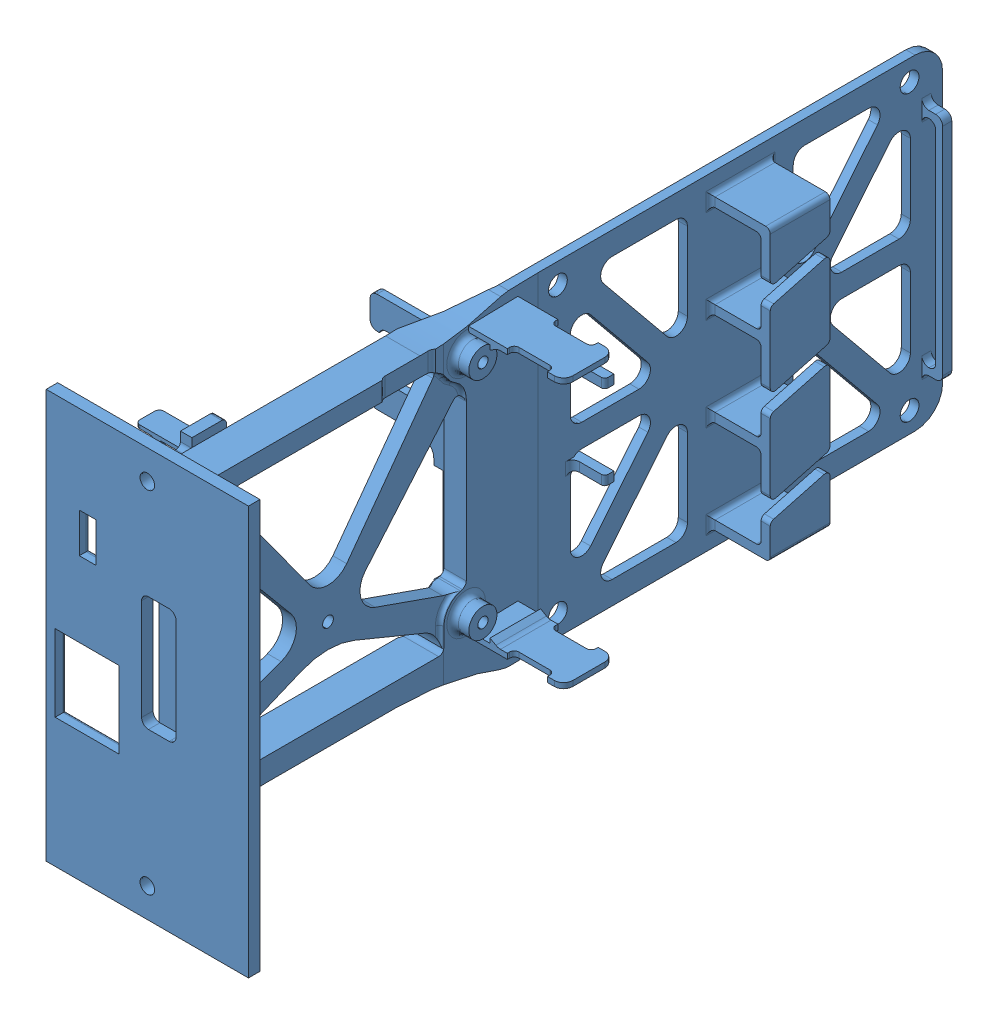
SolidWorks assembly Assem1, configuration Default. Lengths in mm.
Overall size (44 88.9 172.5).
5 component instances, 5 part files, 15 mates.
Components (placement in the parent):
- ODroid_C2.2-1: ODroid_C2.2 [Default] at (4.5 4 -49.5) x (0 0 1) z (1 0 0) size (87.25 57.65 20.75) (hidden)
- POE-1: POE [Default] at (-5.25 -8 -39.305) x (0 0 -1) z (-1 0 0) size (74.68 25.1 17.85) (hidden)
- Rack_base-2: Rack_base [Default] x (-1 0 0) z (0 0 -1) size (44 88.9 172.5)
- ODroid-UART-1: ODroid-UART [Default] at (-11.5 21 -1) x (0 0 -1) z (0 1 0) size (27.4 6.3 13.57) (hidden)
- SSD-1: SSD [Default] at (-1.5 0 -79.5) x (0 0 -1) z (-1 0 0) size (100 70.15 8.25) (hidden)
Mates (geometry in assembly coordinates):
- Coincident12: coincident anti-aligned: plane of Rack_base-2 through (0 0 0) normal (-1 0 0); plane of assembly through (0 0 0) normal (1 0 0)
- Distance7: distance = 0 mm aligned: plane of Rack_base-2; plane of assembly through (0 0 0) normal (0 1 0)
- Coincident3: coincident anti-aligned: plane of Rack_base-2 through (0 0 0) normal (0 0 -1); plane of assembly through (0 0 0) normal (0 0 1)
- Distance1: distance = 7 mm anti-aligned: plane of Rack_base-2 through (0 0 0) normal (0 0 -1); plane of ODroid_C2.2-1 through (0.75 -23.975 -7) normal (0 0 1)
- Distance6: distance = 4.5 mm anti-aligned: plane of ODroid_C2.2-1 through (4.5 4 -49.5) normal (1 0 0); plane of Rack_base-2 through (0 0 0) normal (-1 0 0)
- Distance16: distance = 4 mm anti-aligned: plane of ODroid_C2.2-1; plane of Rack_base-2
- Distance3: distance = 9.75 mm anti-aligned: plane of POE-1 through (-5.25 -8 -39.305) normal (-1 0 0); plane of ODroid_C2.2-1 through (4.5 4 -49.5) normal (1 0 0)
- Coincident17: coincident aligned: plane of POE-1 through (-19.85 -16.15 0) normal (0 0 1); plane of Rack_base-2 through (0 0 0) normal (0 0 1)
- Distance10: distance = 17 mm anti-aligned: plane of ODroid_C2.2-1; plane of ODroid-UART-1 through (-11.5 21 -1) normal (0 1 0)
- Distance8: distance = 1 mm anti-aligned: plane of ODroid-UART-1; plane of Rack_base-2 through (0 0 0) normal (0 0 1)
- Distance11: distance = 16 mm anti-aligned: plane of ODroid-UART-1; plane of ODroid_C2.2-1 through (4.5 4 -49.5) normal (1 0 0)
- Distance12: distance = 12 mm aligned: plane of POE-1; plane of ODroid_C2.2-1
- Distance14: distance = 6 mm anti-aligned: plane of ODroid_C2.2-1 through (4.5 4 -49.5) normal (1 0 0); plane of SSD-1 through (-1.5 0 -79.5) normal (-1 0 0)
- Distance13: distance = 30 mm anti-aligned: plane of ODroid_C2.2-1; plane of SSD-1
- Distance17: distance = 0 mm anti-aligned: plane of Rack_base-2; plane of SSD-1
